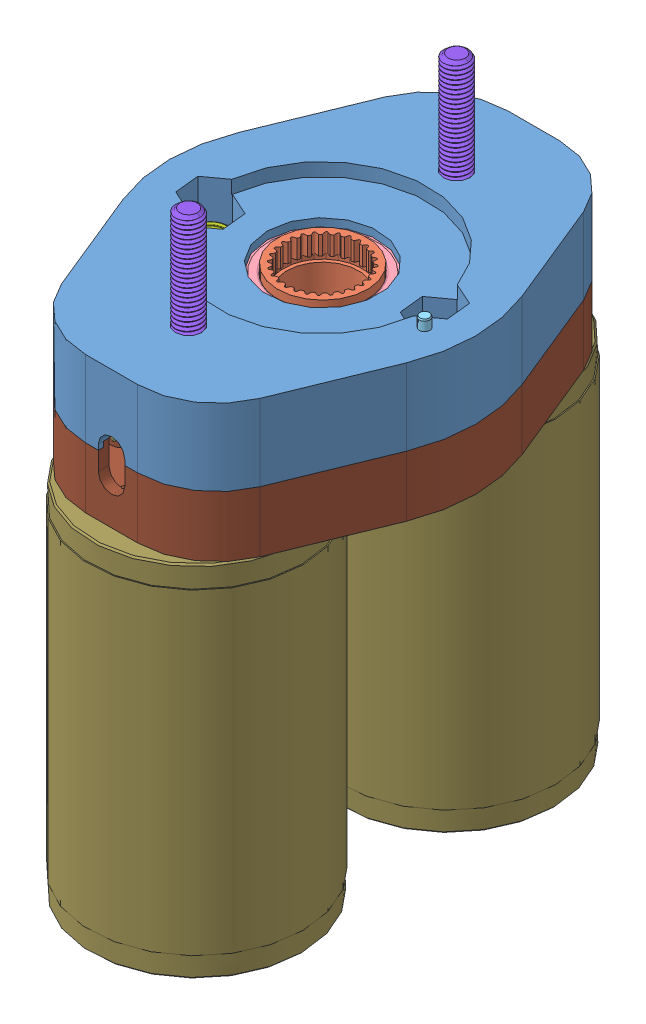
SolidWorks assembly Dual_Motor_Input_with_BAG_Motor, configuration Default. Lengths in mm.
Overall size (58 114.72 88.18).
24 component instances, 13 part files, 0 mates.
Components (placement in the parent):
- 217-3141-001 Rev1-1: 217-3141-001 Rev1 [Default] x (0 0 1) z (-1 0 0) size (80 14.5 58)
- 217-3141-007 Rev1_30T 32DP-1: 217-3141-007 Rev1_30T 32DP [Default] at (0 -7.06 0) x (0 -1 0) z (-0.999183 0 0.040426) size (22.38 25.55 25.47)
- 217-3141-006 Rev1_30T 32DP-1: 217-3141-006 Rev1_30T 32DP [Default] at (0 -9.85 -23.8887) x (-0.095925 0 -0.995389) z (0 -1 0) size (25.47 25.55 10)
- 217-3141-006 Rev1_30T 32DP-2: 217-3141-006 Rev1_30T 32DP [Default] at (0 -9.85 23.8887) x (-0.001725 0 0.999999) z (0 -1 0) size (25.47 25.55 10)
- 217-2741-1: 217-2741 [Default] at (0 2.75 0) x (0 -1 0) z (-0.999445 0 -0.033298) size (5 26 26)
- 217-2741-2: 217-2741 [Default] at (0 -13.25 0) x (0 -1 0) z (-0.537831 0 0.843053) size (5 26 26)
- PINL-M020-006-S-1: PINL-M020-006-S [Default] at (22.7445 5.75 3.4184) x (0 1 0) z (-0.890225 0 0.455522) size (6 2 2)
- SSS1032-0188-ZB-1: SSS1032-0188-ZB [Default] at (-0.3489 -11.725 -27.5094) x (-0.758755 -0.647259 0.073121) z (0.095925 0 0.995389) size (4.91 4.91 5.06)
- SSS1032-0188-ZB-2: SSS1032-0188-ZB [Default] at (-0.0063 -11.725 27.5262) x (0.762269 -0.647259 0.001315) z (0.001725 0 -0.999999) size (4.91 4.91 5.06)
- NUT-832-NYLOCK-1: NUT-832-NYLOCK [Default] at (19.244 -4.75 -2.0226) x (0.913545 0 0.406737) z (-0.406737 0 0.913545) size (10.2 4.9 8.12)
- NUT-832-NYLOCK-2: NUT-832-NYLOCK [Default] at (-19.244 -4.75 2.0226) x (0.912648 0 0.408747) z (-0.408747 0 0.912648) size (10.2 4.9 8.12)
- 91251A346_91251A346-1: 91251A346_91251A346 [Default] at (0 25.975 25.4) x (1 0 0) z (0 1 0) size (7.92 7.92 27.28)
- 91251A346_91251A346-2: 91251A346_91251A346 [Default] at (0 25.975 -25.4) x (1 0 0) z (0 1 0) size (7.92 7.92 27.28)
- SSA_SSAM4-0010ZC-1: SSA_SSAM4-0010ZC [Default] at (12.5 -17.25 -23.8887) size (7 14 7)
- SSA_SSA0832-0750ZC-1: SSA_SSA0832-0750ZC [Default] at (19.244 -19.25 -2.0226) x (-0.091926 0 -0.995766) z (-0.995766 0 0.091926) size (6.73 23.11 6.73)
- SSA_SSA0832-0750ZC-2: SSA_SSA0832-0750ZC [Default] at (-19.244 -19.25 2.0226) x (-0.18632 0 -0.982489) z (-0.982489 0 0.18632) size (6.73 23.11 6.73)
- SSA_SSAM4-0010ZC-2: SSA_SSAM4-0010ZC [Default] at (-12.5 -17.25 23.8887) x (0.677756 0 0.735287) z (-0.735287 0 0.677756) size (7 14 7)
- SSA_SSAM4-0010ZC-3: SSA_SSAM4-0010ZC [Default] at (12.5 -17.25 23.8887) x (0.994338 0 -0.106265) z (0.106265 0 0.994338) size (7 14 7)
- SSA_SSAM4-0010ZC-4: SSA_SSAM4-0010ZC [Default] at (-12.5 -17.25 -23.8887) x (0.537906 0 -0.843005) z (0.843005 0 0.537906) size (7 14 7)
- 217-3141-002 Rev2-1: 217-3141-002 Rev2 [Default] at (0 -13 0) x (0 0 1) z (0 1 0) size (80 58 12.5)
- 217-3351-1: 217-3351 [Default] at (0 -19.25 -23.8887) x (1 0 0) z (0 1 0) size (40.4 40.4 81.5)
- 217-3351-2: 217-3351 [Default] at (0 -19.25 23.8887) x (1 0 0) z (0 1 0) size (40.4 40.4 81.5)
- 217-2625-011 Rev1-1: 217-2625-011 Rev1 [Default] at (0 -11.1 -23.8887) x (0.095925 0 0.995389) z (-0.995389 0 0.095925) size (8.01 7.5 7.94)
- 217-2625-011 Rev1-2: 217-2625-011 Rev1 [Default] at (0 -11 23.8887) x (-0.964857 0 0.262777) z (-0.262777 0 -0.964857) size (8.01 7.5 7.94)
